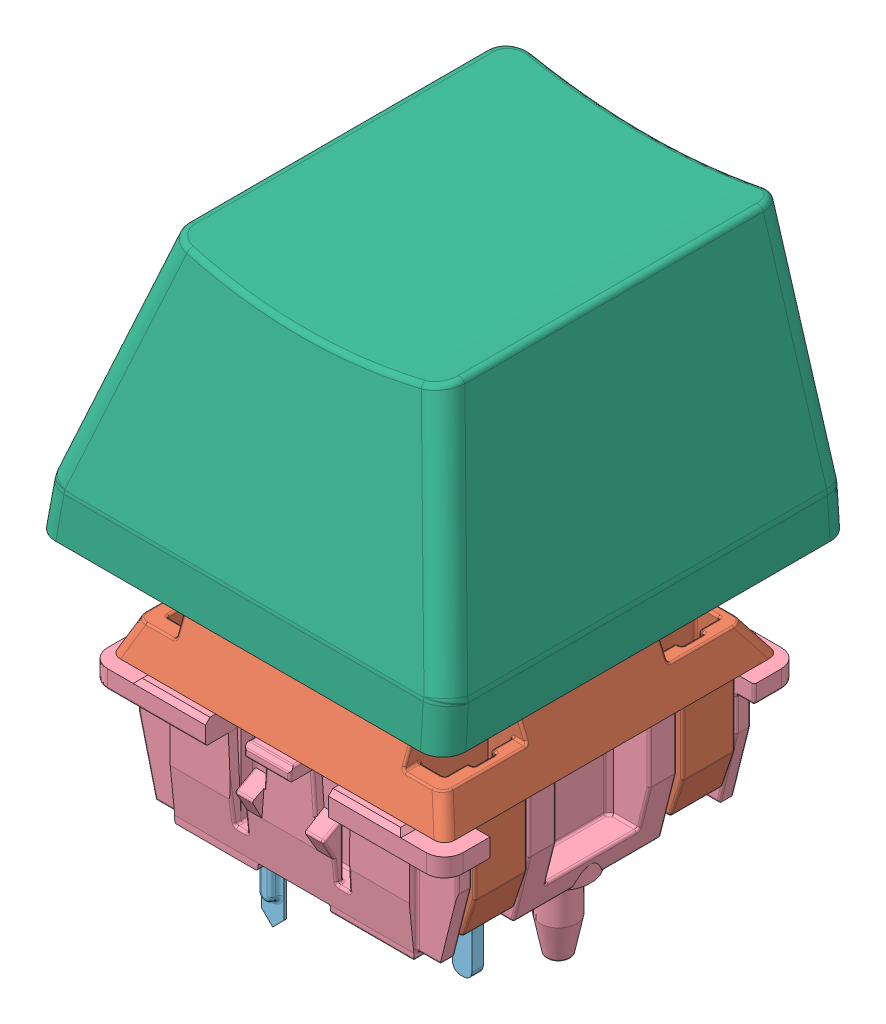
SolidWorks assembly MX 按键, configuration Default. Lengths in mm.
Overall size (18 25.69 18.06).
7 component instances, 7 part files, 8 mates.
Components (placement in the parent):
- MX 轴 按键-1: MX 轴 按键 [Default] at (7.35 2 -7.35) size (8.9 10.4 5.7)
- MX 轴 轴体-1: MX 轴 轴体 [Default] at origin size (14.7 9.91 14.7)
- MX轴 无帽LED-1: MX轴 无帽LED [Default] at (7.35 0.5 -12.292) size (3 15.3 3)
- 机箱用方开关键帽 1574-1: 机箱用方开关键帽 1574 [Default] at (7.35 5.7 -7.35) (suppressed, hidden)
- MX轴 轴体 底部-1: MX轴 轴体 底部 [默认] at (7.35 -0.2 -7.35) size (15.6 12.5 15.6)
- 针脚-2: 针脚 [默认] at (-5.5727 -8.7 12.741) size (7.15 6.7 2.96)
- MX 轴标准键帽-1: MX 轴标准键帽 [默认] at (-1.6779 4.7456 -16.3119) size (18 11.44 18.06)
Mates (geometry in assembly coordinates):
- Distance1: distance = 0.15 mm anti-aligned: plane of MX 轴 轴体-1 through (3.45 1.4 -4.35) normal (0 0 -1); plane of MX 轴 按键-1 through (3.7 5.2 -4.5) normal (0 0 1)
- Distance2: distance = 0.25 mm anti-aligned: plane of MX 轴 轴体-1 through (3.45 1.4 -10.35) normal (1 0 0); plane of MX 轴 按键-1 through (3.7 5.2 -10.2) normal (-1 0 0)
- Coincident4: coincident anti-aligned: plane of MX 轴 轴体-1 through (0 0 0) normal (0 -1 0); plane of MX轴 轴体 底部-1 through (7.35 0 -7.35) normal (0 1 0)
- LimitDistance2: limit distance = -0.5 mm aligned: plane of MX 轴 按键-1 through (7.35 5.7 -7.35) normal (0 1 0); plane of MX 轴 轴体-1 through (0 5.2 0) normal (0 1 0)
- Coincident10: coincident anti-aligned: plane of MX轴 轴体 底部-1 through (10.6 -0.9 -4.95) normal (0 0 1); plane of 针脚-2 through (10.6 -2.5 -4.95) normal (0 0 -1)
- Coincident11: coincident anti-aligned: plane of MX轴 轴体 底部-1 through (10.6 -0.9 -4.95) normal (1 0 0); plane of 针脚-2 through (10.6 -2.5 -4.95) normal (-1 0 0)
- Concentric1: concentric anti-aligned: cylinder of MX 轴 轴体-1 through (7.35 0.5 -12.292) axis (0 1 0) radius 1.6; cylinder of MX轴 无帽LED-1 through (7.35 5.8 -12.292) axis (0 -1 0) radius 1.5
- Coincident12: coincident anti-aligned: plane of MX 轴 轴体-1 through (7.35 0.5 -12.292) normal (0 1 0); plane of MX轴 无帽LED-1 through (7.35 0.5 -12.292) normal (0 -1 0)
